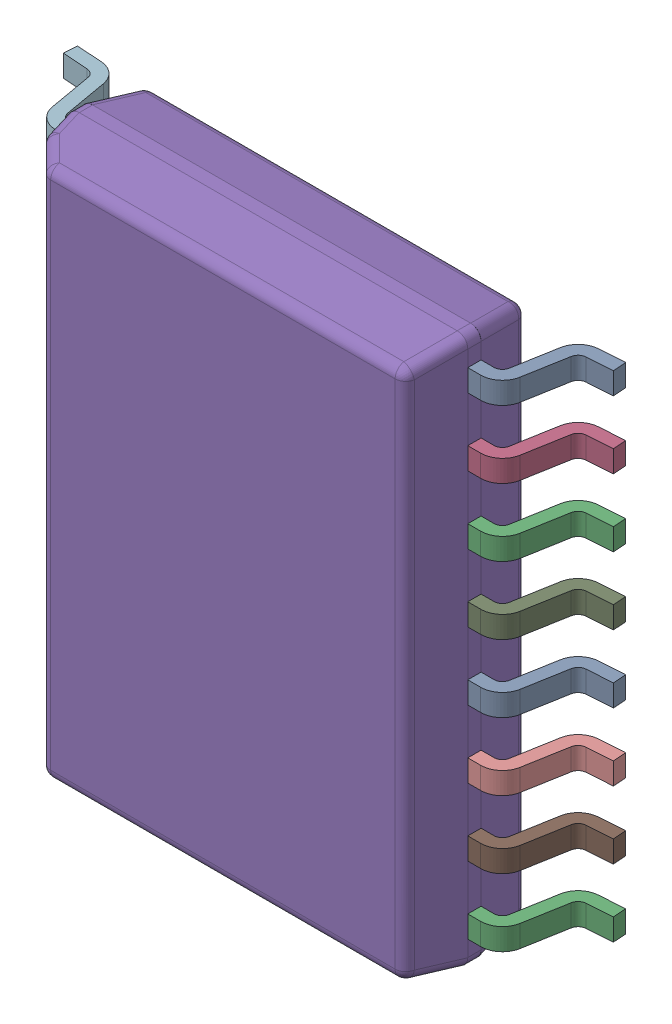
SolidWorks assembly IC9, configuration По умолчанию. Lengths in mm.
Overall size (10.33 10.3 2.59).
18 component instances, 2 part files, 0 mates.
Components (placement in the parent):
- DW0016B_ASM-1: DW0016B_ASM [По умолчанию] at origin size (10.33 10.3 2.59)
  - DW0016B_ASM-Part-1-1: DW0016B_ASM-Part-1 [По умолчанию] at (4.315 -0.635 0.25) x (0 1 0) z (1 0 0) size (0.41 1.57 1.42)
  - DW0016B_ASM-Part-1-2: DW0016B_ASM-Part-1 [По умолчанию] at (-4.315 -1.905 0.25) x (0 -1 0) z (-1 0 0) size (0.41 1.57 1.42)
  - DW0016B_ASM-Part-1-3: DW0016B_ASM-Part-1 [По умолчанию] at (4.315 -4.445 0.25) x (0 1 0) z (1 0 0) size (0.41 1.57 1.42)
  - DW0016B_ASM-Part-1-4: DW0016B_ASM-Part-1 [По умолчанию] at (4.315 3.175 0.25) x (0 1 0) z (1 0 0) size (0.41 1.57 1.42)
  - DW0016B_ASM-Part-1-5: DW0016B_ASM-Part-1 [По умолчанию] at (-4.315 0.635 0.25) x (0 -1 0) z (-1 0 0) size (0.41 1.57 1.42)
  - DW0016B_ASM-Part-1-6: DW0016B_ASM-Part-1 [По умолчанию] at (-4.315 -3.175 0.25) x (0 -1 0) z (-1 0 0) size (0.41 1.57 1.42)
  - DW0016B_ASM-Part-1-7: DW0016B_ASM-Part-1 [По умолчанию] at (-4.315 -4.445 0.25) x (0 -1 0) z (-1 0 0) size (0.41 1.57 1.42)
  - DW0016B_ASM-Part-1-8: DW0016B_ASM-Part-1 [По умолчанию] at (-4.315 3.175 0.25) x (0 -1 0) z (-1 0 0) size (0.41 1.57 1.42)
  - DW0016B_ASM-Part-1-9: DW0016B_ASM-Part-1 [По умолчанию] at (4.315 0.635 0.25) x (0 1 0) z (1 0 0) size (0.41 1.57 1.42)
  - DW0016B_ASM-Part-1-10: DW0016B_ASM-Part-1 [По умолчанию] at (4.315 -1.905 0.25) x (0 1 0) z (1 0 0) size (0.41 1.57 1.42)
  - DW0016B_ASM-Part-1-11: DW0016B_ASM-Part-1 [По умолчанию] at (4.315 -3.175 0.25) x (0 1 0) z (1 0 0) size (0.41 1.57 1.42)
  - DW0016B_ASM-Part-1-12: DW0016B_ASM-Part-1 [По умолчанию] at (-4.315 4.445 0.25) x (0 -1 0) z (-1 0 0) size (0.41 1.57 1.42)
  - DW0016B_ASM-Part-1-13: DW0016B_ASM-Part-1 [По умолчанию] at (4.315 4.445 0.25) x (0 1 0) z (1 0 0) size (0.41 1.57 1.42)
  - DW0016B_ASM-Part-1-14: DW0016B_ASM-Part-1 [По умолчанию] at (-4.315 1.905 0.25) x (0 -1 0) z (-1 0 0) size (0.41 1.57 1.42)
  - DW0016B_ASM-Part-1-15: DW0016B_ASM-Part-1 [По умолчанию] at (4.315 1.905 0.25) x (0 1 0) z (1 0 0) size (0.41 1.57 1.42)
  - DW0016B_ASM-Part-1-16: DW0016B_ASM-Part-1 [По умолчанию] at (-4.315 -0.635 0.25) x (0 -1 0) z (-1 0 0) size (0.41 1.57 1.42)
  - DW0016B_ASM-Part-2-1: DW0016B_ASM-Part-2 [По умолчанию] at (0 0 1.568) x (0 1 0) z (1 0 0) size (10.3 2.29 7.5)
